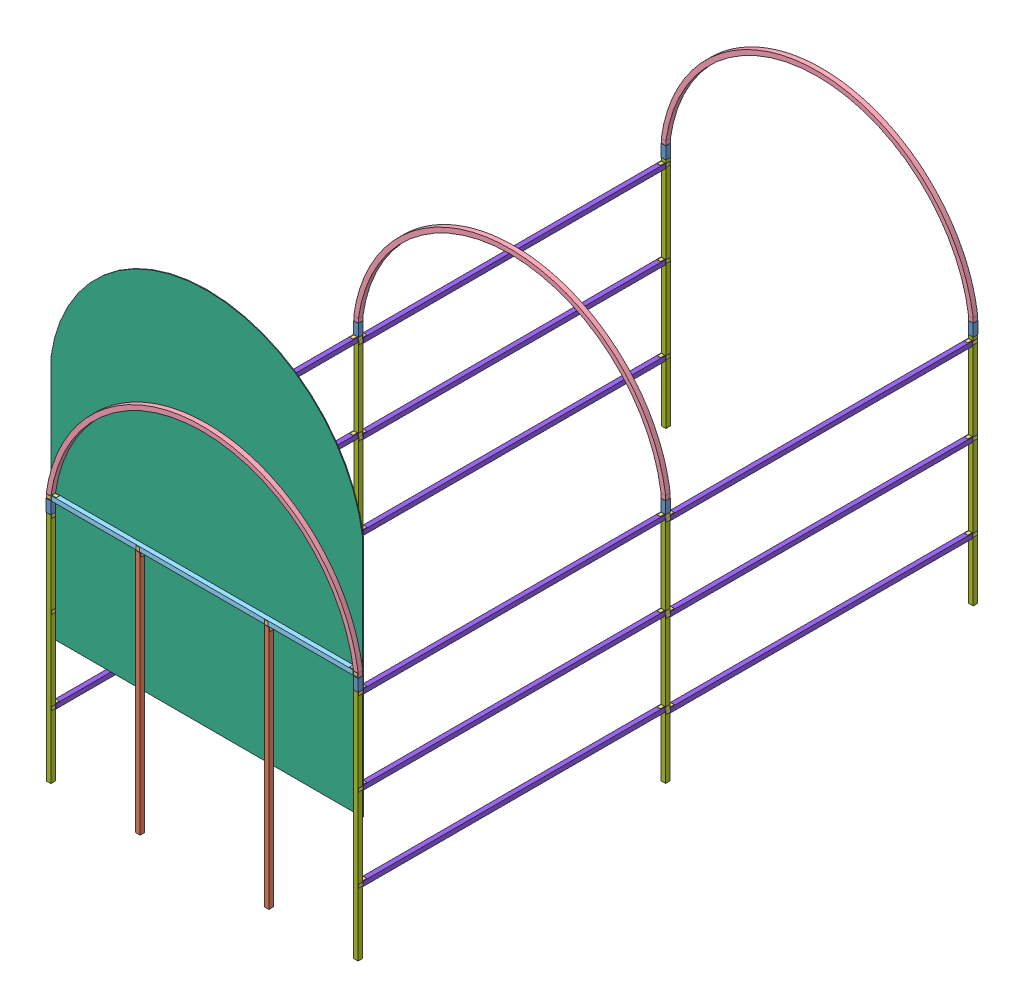
SolidWorks assembly SolarDrying, configuration Default. Lengths in mm.
Overall size (2062 2546.04 4095).
87 component instances, 8 part files, 50 mates.
Components (placement in the parent):
- Vertical joint-1: Vertical joint [Default] at (-1015 770.5 -2037.8) size (32 80 32)
- VerticalBar-1: VerticalBar [Default] at (-425 0 -2037.8) x (-1 0 0) z (0 0 1) size (30 1615 30)
- Wrapper-1: Wrapper [Default] at (-425 780.5 -2037.8) x (0 0 -1) z (0 1 0) size (22 32 30)
- Arc_Bar-1: Arc_Bar [Default] at (0 838.5301 -2037.8) x (0 0 -1) z (1 0 0) size (30.03 960.01 2060)
- LateralBar-1: LateralBar [Default] at (0 826.5 -2037.8) x (0 0 -1) z (1 0 0) size (30 30 1992)
- Back_Wall-1: Back_Wall [Default] at (0 800 -2055.3) size (2060 2500 5) (hidden)
- Wrapper-4: Wrapper [Default] at (-1027 826.5 -2037.8) x (0 1 0) z (1 0 0) size (22 32 30)
- Wrapper-5: Wrapper [Default] at (-969 826.5 -2037.8) x (0 0 1) z (-1 0 0) size (22 32 30)
- VerticalBar_Corners-1: VerticalBar_Corners [Default] at (-1015 -14.4849 -2037.8) size (30 1586.03 30)
- Wrapper-8: Wrapper [Default] at (-425 838.5 -2037.8) x (1 0 0) z (0 -1 0) size (22 32 30)
- VerticalBar-2: VerticalBar [Default] at (425 0 -2037.8) x (1 0 0) z (0 0 -1) size (30 1615 30)
- Wrapper-9: Wrapper [Default] at (425 838.5 -2037.8) x (1 0 0) z (0 -1 0) size (22 32 30)
- Wrapper-10: Wrapper [Default] at (425 780.5 -2037.8) x (0 0 1) z (0 1 0) size (22 32 30)
- VerticalBar_Corners-2: VerticalBar_Corners [Default] at (1015 -14.4849 -2037.8) x (-1 0 0) z (0 0 -1) size (30 1586.03 30)
- Vertical joint-2: Vertical joint [Default] at (1015 770.5 -2037.8) x (-1 0 0) z (0 0 -1) size (32 80 32)
- Wrapper-11: Wrapper [Default] at (1027 826.5 -2037.8) x (0 -1 0) z (-1 0 0) size (22 32 30)
- Wrapper-12: Wrapper [Default] at (969 826.5 -2037.8) x (0 0 -1) z (1 0 0) size (22 32 30)
- VerticalBar_Corners-7: VerticalBar_Corners [Default] at (-1015 -14.4849 -4069.3) size (30 1586.03 30)
- VerticalBar_Corners-8: VerticalBar_Corners [Default] at (-1015 -14.4849 -6100.8) size (30 1586.03 30)
- Vertical joint-7: Vertical joint [Default] at (-1015 770.5 -4069.3) size (32 80 32)
- Vertical joint-8: Vertical joint [Default] at (-1015 770.5 -6100.8) size (32 80 32)
- VerticalBar_Corners-9: VerticalBar_Corners [Default] at (1015 -14.4849 -4069.3) x (-1 0 0) z (0 0 -1) size (30 1586.03 30)
- VerticalBar_Corners-10: VerticalBar_Corners [Default] at (1015 -14.4849 -6100.8) x (-1 0 0) z (0 0 -1) size (30 1586.03 30)
- Vertical joint-9: Vertical joint [Default] at (1015 770.5 -4069.3) x (-1 0 0) z (0 0 -1) size (32 80 32)
- Vertical joint-10: Vertical joint [Default] at (1015 770.5 -6100.8) x (-1 0 0) z (0 0 -1) size (32 80 32)
- Arc_Bar-4: Arc_Bar [Default] at (0 838.5301 -4069.3) x (0 0 -1) z (1 0 0) size (30.03 960.01 2060)
- Arc_Bar-5: Arc_Bar [Default] at (0 838.5301 -6100.8) x (0 0 -1) z (1 0 0) size (30.03 960.01 2060)
- Wrapper-13: Wrapper [Default] at (1015 719.5 -2025.8) x (0 1 0) z (0 0 -1) size (22 32 30)
- Wrapper-15: Wrapper [Default] at (1015 717.5 -2083.8) size (22 32 30)
- Wrapper-16: Wrapper [Default] at (1015 719.5 -4081.3) x (0 -1 0) z (0 0 1) size (22 32 30)
- Wrapper-17: Wrapper [Default] at (1015 717.5 -4023.3) x (-1 0 0) z (0 0 -1) size (22 32 30)
- HorizontalBarSides-1: HorizontalBarSides [Default] at (1015 717.5 -4051.3) size (30 30 1995.5)
- Wrapper-22: Wrapper [Default] at (1015 697.5 -4057.3) x (0 1 0) z (0 0 -1) size (22 32 30)
- Wrapper-23: Wrapper [Default] at (1015 695.5 -4115.3) size (22 32 30)
- HorizontalBarSides-3: HorizontalBarSides [Default] at (1015 695.5 -6082.8) size (30 30 1995.5)
- Wrapper-24: Wrapper [Default] at (1015 697.5 -6112.8) x (0 -1 0) z (0 0 1) size (22 32 30)
- Wrapper-25: Wrapper [Default] at (1015 695.5 -6054.8) x (-1 0 0) z (0 0 -1) size (22 32 30)
- Wrapper-26: Wrapper [Default] at (1015 147.5 -6112.8) x (0 -1 0) z (0 0 1) size (22 32 30)
- Wrapper-27: Wrapper [Default] at (1015 -402.5 -6112.8) x (0 -1 0) z (0 0 1) size (22 32 30)
- Wrapper-28: Wrapper [Default] at (1015 145.5 -6054.8) x (-1 0 0) z (0 0 -1) size (22 32 30)
- Wrapper-29: Wrapper [Default] at (1015 -404.5 -6054.8) x (-1 0 0) z (0 0 -1) size (22 32 30)
- HorizontalBarSides-4: HorizontalBarSides [Default] at (1015 145.5 -6082.8) size (30 30 1995.5)
- HorizontalBarSides-5: HorizontalBarSides [Default] at (1015 -404.5 -6082.8) size (30 30 1995.5)
- Wrapper-30: Wrapper [Default] at (1015 145.5 -4115.3) size (22 32 30)
- Wrapper-31: Wrapper [Default] at (1015 -404.5 -4115.3) size (22 32 30)
- Wrapper-32: Wrapper [Default] at (1015 147.5 -4057.3) x (0 1 0) z (0 0 -1) size (22 32 30)
- Wrapper-33: Wrapper [Default] at (1015 -402.5 -4057.3) x (0 1 0) z (0 0 -1) size (22 32 30)
- Wrapper-34: Wrapper [Default] at (1015 169.5 -4081.3) x (0 -1 0) z (0 0 1) size (22 32 30)
- Wrapper-35: Wrapper [Default] at (1015 -380.5 -4081.3) x (0 -1 0) z (0 0 1) size (22 32 30)
- Wrapper-36: Wrapper [Default] at (1015 167.5 -4023.3) x (-1 0 0) z (0 0 -1) size (22 32 30)
- Wrapper-37: Wrapper [Default] at (1015 -382.5 -4023.3) x (-1 0 0) z (0 0 -1) size (22 32 30)
- HorizontalBarSides-6: HorizontalBarSides [Default] at (1015 167.5 -4051.3) size (30 30 1995.5)
- HorizontalBarSides-7: HorizontalBarSides [Default] at (1015 -382.5 -4051.3) size (30 30 1995.5)
- Wrapper-38: Wrapper [Default] at (1015 169.5 -2025.8) x (0 1 0) z (0 0 -1) size (22 32 30)
- Wrapper-39: Wrapper [Default] at (1015 -380.5 -2025.8) x (0 1 0) z (0 0 -1) size (22 32 30)
- Wrapper-40: Wrapper [Default] at (1015 167.5 -2083.8) size (22 32 30)
- Wrapper-41: Wrapper [Default] at (1015 -382.5 -2083.8) size (22 32 30)
- Wrapper-42: Wrapper [Default] at (-1015 697.5 -6112.8) x (0 1 0) z (0 0 1) size (22 32 30)
- Wrapper-43: Wrapper [Default] at (-1015 695.5 -6054.8) x (-1 0 0) z (0 0 -1) size (22 32 30)
- HorizontalBarSides-8: HorizontalBarSides [Default] at (-1015 695.5 -4087.3) x (-1 0 0) z (0 0 -1) size (30 30 1995.5)
- Wrapper-44: Wrapper [Default] at (-1015 695.5 -4115.3) size (22 32 30)
- Wrapper-45: Wrapper [Default] at (-1015 697.5 -4057.3) x (0 -1 0) z (0 0 -1) size (22 32 30)
- Wrapper-46: Wrapper [Default] at (-1015 719.5 -4081.3) x (0 1 0) z (0 0 1) size (22 32 30)
- Wrapper-47: Wrapper [Default] at (-1015 717.5 -4023.3) x (-1 0 0) z (0 0 -1) size (22 32 30)
- HorizontalBarSides-9: HorizontalBarSides [Default] at (-1015 717.5 -2055.8) x (-1 0 0) z (0 0 -1) size (30 30 1995.5)
- Wrapper-48: Wrapper [Default] at (-1015 719.5 -2025.8) x (0 -1 0) z (0 0 -1) size (22 32 30)
- Wrapper-49: Wrapper [Default] at (-1015 717.5 -2083.8) size (22 32 30)
- Wrapper-50: Wrapper [Default] at (-1015 147.5 -6112.8) x (0 1 0) z (0 0 1) size (22 32 30)
- Wrapper-51: Wrapper [Default] at (-1015 -402.5 -6112.8) x (0 1 0) z (0 0 1) size (22 32 30)
- Wrapper-52: Wrapper [Default] at (-1015 145.5 -6054.8) x (-1 0 0) z (0 0 -1) size (22 32 30)
- Wrapper-53: Wrapper [Default] at (-1015 -404.5 -6054.8) x (-1 0 0) z (0 0 -1) size (22 32 30)
- HorizontalBarSides-10: HorizontalBarSides [Default] at (-1015 145.5 -4087.3) x (-1 0 0) z (0 0 -1) size (30 30 1995.5)
- HorizontalBarSides-11: HorizontalBarSides [Default] at (-1015 -404.5 -4087.3) x (-1 0 0) z (0 0 -1) size (30 30 1995.5)
- Wrapper-54: Wrapper [Default] at (-1015 145.5 -4115.3) size (22 32 30)
- Wrapper-55: Wrapper [Default] at (-1015 -404.5 -4115.3) size (22 32 30)
- Wrapper-56: Wrapper [Default] at (-1015 147.5 -4057.3) x (0 -1 0) z (0 0 -1) size (22 32 30)
- Wrapper-57: Wrapper [Default] at (-1015 -402.5 -4057.3) x (0 -1 0) z (0 0 -1) size (22 32 30)
- Wrapper-58: Wrapper [Default] at (-1015 169.5 -4081.3) x (0 1 0) z (0 0 1) size (22 32 30)
- Wrapper-59: Wrapper [Default] at (-1015 -380.5 -4081.3) x (0 1 0) z (0 0 1) size (22 32 30)
- Wrapper-60: Wrapper [Default] at (-1015 167.5 -4023.3) x (-1 0 0) z (0 0 -1) size (22 32 30)
- Wrapper-61: Wrapper [Default] at (-1015 -382.5 -4023.3) x (-1 0 0) z (0 0 -1) size (22 32 30)
- HorizontalBarSides-12: HorizontalBarSides [Default] at (-1015 167.5 -2055.8) x (-1 0 0) z (0 0 -1) size (30 30 1995.5)
- HorizontalBarSides-13: HorizontalBarSides [Default] at (-1015 -382.5 -2055.8) x (-1 0 0) z (0 0 -1) size (30 30 1995.5)
- Wrapper-62: Wrapper [Default] at (-1015 169.5 -2025.8) x (0 -1 0) z (0 0 -1) size (22 32 30)
- Wrapper-63: Wrapper [Default] at (-1015 -380.5 -2025.8) x (0 -1 0) z (0 0 -1) size (22 32 30)
- Wrapper-64: Wrapper [Default] at (-1015 167.5 -2083.8) size (22 32 30)
- Wrapper-65: Wrapper [Default] at (-1015 -382.5 -2083.8) size (22 32 30)
Mates (geometry in assembly coordinates):
- Coincident1: coincident anti-aligned: plane of Back_Wall-1 through (1030 0 -2052.8) normal (0 -1 0)
- Distance1: distance = 2052.8 mm aligned: plane of Back_Wall-1 through (0 1460.6111 -2052.8) normal (0 0 1)
- Coincident6: coincident anti-aligned: plane of LateralBar-1 through (996 811.5 -2052.8) normal (0 0 -1); plane of Back_Wall-1 through (0 1460.6111 -2052.8) normal (0 0 1)
- Coincident12: coincident aligned: plane of Back_Wall-1 through (0 800 -2055.3) normal (1 0 0)
- Coincident15: coincident anti-aligned: plane of LateralBar-1 through (996 841.5 -2022.8) normal (0 1 0); plane of Wrapper-5 through (-996 841.5 -2048.8) normal (0 -1 0)
- Coincident16: coincident anti-aligned: plane of LateralBar-1 through (996 811.5 -2022.8) normal (0 -1 0); plane of Wrapper-5 through (-969 811.5 -2048.8) normal (0 1 0)
- Parallel4: parallel aligned: plane of LateralBar-1 through (996 811.5 -2052.8) normal (0 0 -1); plane of Wrapper-5 through (-996 842.5 -2048.8) normal (0 0 -1)
- Coincident19: coincident anti-aligned: plane of LateralBar-1 through (0 826.5 -2037.8) normal (0 0 -1); plane of Wrapper-5 through (-969 826.5 -2037.8) normal (0 0 1)
- Coincident23: coincident anti-aligned: plane of Wrapper-4 through (-998 815.5 -2050.8) normal (-1 0 0); plane of Wrapper-5 through (-998 813.5 -2048.8) normal (1 0 0)
- Coincident25: coincident aligned: plane of Wrapper-4 through (-1027 826.5 -2037.8) normal (0 1 0); plane of Wrapper-5 through (-969 826.5 -2037.8) normal (0 1 0)
- Coincident26: coincident aligned: plane of Arc_Bar-1; plane of LateralBar-1 through (0 826.5 -2037.8) normal (1 0 0)
- Coincident27: coincident aligned: plane of Arc_Bar-1; plane of LateralBar-1 through (0 826.5 -2037.8) normal (1 0 0)
- Parallel5: parallel anti-aligned: line of Arc_Bar-1 through (-1000 837.5 -2022.8) axis (0 0 -1); line of LateralBar-1 through (-996 841.5 -2052.8) axis (0 0 1)
- Coincident31: coincident: point of Arc_Bar-1; point of Wrapper-4
- Coincident32: coincident anti-aligned: plane of Vertical joint-1 through (-1000 810.5 -2052.8) normal (0 0 1); plane of Arc_Bar-1 through (0 778.5301 -2052.8) normal (0 0 -1)
- Coincident33: coincident anti-aligned: plane of Vertical joint-1 through (-1030 810.5 -2052.8) normal (1 0 0); plane of Arc_Bar-1 through (-1030 778.5301 -2037.8) normal (-1 0 0)
- Coincident34: coincident anti-aligned: plane of Wrapper-4 through (-998 815.5 -2050.8) normal (-1 0 0); plane of Wrapper-5 through (-998 813.5 -2048.8) normal (1 0 0)
- Coincident35: coincident aligned: plane of Wrapper-4 through (-1027 826.5 -2037.8) normal (0 0 1); plane of Wrapper-5 through (-969 826.5 -2037.8) normal (0 0 1)
- Coincident36: coincident anti-aligned: plane of Vertical joint-1 through (-1015 810.5 -2037.8) normal (0 1 0); plane of Wrapper-5 through (-969 810.5 -2048.8) normal (0 -1 0)
- Coincident42: coincident anti-aligned: line of VerticalBar-1 through (-410 807.5 -2052.8) axis (0 0 1); line of Wrapper-1 through (-410 807.5 -2026.8) axis (0 0 -1)
- Coincident43: coincident aligned: line of VerticalBar-1 through (-440 807.5 -2022.8) axis (0 0 -1); line of Wrapper-1 through (-440 807.5 -2026.8) axis (0 0 -1)
- Coincident44: coincident anti-aligned: plane of VerticalBar-1 through (-425 0 -2037.8) normal (0 0 1); plane of Wrapper-1 through (-425 780.5 -2037.8) normal (0 0 -1)
- Coincident45: coincident anti-aligned: plane of VerticalBar-1 through (-425 0 -2037.8) normal (0 0 1); plane of LateralBar-1 through (0 826.5 -2037.8) normal (0 0 -1)
- Parallel6: parallel anti-aligned: plane of VerticalBar-1 through (-425 0 -2037.8) normal (-1 0 0); plane of LateralBar-1 through (0 826.5 -2037.8) normal (1 0 0)
- Distance3: distance = 425 mm anti-aligned: plane of VerticalBar-1 through (-425 0 -2037.8) normal (-1 0 0); plane of LateralBar-1 through (0 826.5 -2037.8) normal (1 0 0)
- Coincident48: coincident anti-aligned: plane of Wrapper-1 through (-412 809.5 -2026.8) normal (0 -1 0); plane of Wrapper-8 through (-436 809.5 -2050.8) normal (0 1 0)
- Coincident49: coincident anti-aligned: plane of Wrapper-1 through (-425 780.5 -2037.8) normal (-1 0 0); plane of Wrapper-8 through (-425 838.5 -2037.8) normal (1 0 0)
- Coincident50: coincident anti-aligned: plane of Wrapper-1 through (-425 780.5 -2037.8) normal (0 0 -1); plane of Wrapper-8 through (-425 838.5 -2037.8) normal (0 0 1)
- Coincident51: coincident anti-aligned: line of LateralBar-1 through (996 811.5 -2022.8) axis (-1 0 0); line of Wrapper-8 through (-436 811.5 -2022.8) axis (1 0 0)
- Coincident52: coincident anti-aligned: plane of Arc_Bar-1 through (0 778.5301 -2037.8) normal (0 -1 0); plane of VerticalBar_Corners-1 through (-1015 778.5301 -2037.8) normal (0 1 0)
- Coincident53: coincident anti-aligned: plane of Vertical joint-1 through (-1000 810.5 -2052.8) normal (0 0 1); plane of VerticalBar_Corners-1 through (-1030 778.5301 -2052.8) normal (0 0 -1)
- Coincident54: coincident anti-aligned: plane of Vertical joint-1 through (-1000 810.5 -2052.8) normal (-1 0 0); plane of VerticalBar_Corners-1 through (-1000 778.5301 -2052.8) normal (1 0 0)
- Coincident57: coincident anti-aligned: plane of VerticalBar-1 through (-425 0 -2037.8) normal (0 -1 0)
- Coincident58: coincident anti-aligned: line of VerticalBar_Corners-2 through (1000 778.5301 -2052.8) axis (0 -1 0); line of Wrapper-13 through (1000 708.5 -2052.8) axis (0 1 0)
- Coincident59: coincident anti-aligned: line of VerticalBar_Corners-2 through (1030 778.5301 -2052.8) axis (0 -1 0); line of Wrapper-13 through (1030 708.5 -2052.8) axis (0 1 0)
- Coincident60: coincident aligned: plane of Wrapper-13 through (1015 719.5 -2025.8) normal (1 0 0); plane of Wrapper-15 through (1015 717.5 -2083.8) normal (1 0 0)
- Coincident61: coincident aligned: plane of Wrapper-13 through (1015 719.5 -2025.8) normal (1 0 0); plane of Wrapper-15 through (1015 717.5 -2083.8) normal (1 0 0)
- Coincident63: coincident anti-aligned: plane of Wrapper-13 through (1002 708.5 -2054.8) normal (0 0 1); plane of Wrapper-15 through (1004 704.5 -2054.8) normal (0 0 -1)
- Coincident64: coincident anti-aligned: plane of Vertical joint-2 through (1015 730.5 -2037.8) normal (0 -1 0); plane of Wrapper-13 through (1031 730.5 -2052.8) normal (0 1 0)
- Coincident65: coincident aligned: line of Wrapper-13 through (1002 730.5 -2054.8) axis (1 0 0); line of Wrapper-15 through (1004 730.5 -2054.8) axis (1 0 0)
- Coincident67: coincident aligned: line of VerticalBar_Corners-9 through (1000 778.5301 -4054.3) axis (0 -1 0); line of Wrapper-16 through (1000 730.5 -4054.3) axis (0 -1 0)
- Coincident68: coincident aligned: unknown of Arc_Bar-1
- Coincident69: coincident aligned: line of VerticalBar_Corners-9 through (1030 778.5301 -4054.3) axis (0 -1 0); line of Wrapper-16 through (1030 730.5 -4054.3) axis (0 -1 0)
- Coincident70: coincident anti-aligned: plane of Vertical joint-9 through (1015 730.5 -4069.3) normal (0 -1 0); plane of Wrapper-16 through (1031 730.5 -4054.3) normal (0 1 0)
- Coincident71: coincident anti-aligned: plane of Wrapper-16 through (1002 730.5 -4052.3) normal (0 0 -1); plane of Wrapper-17 through (1026 704.5 -4052.3) normal (0 0 1)
- Coincident72: coincident anti-aligned: line of Wrapper-16 through (1002 730.5 -4052.3) axis (1 0 0); line of Wrapper-17 through (1026 730.5 -4052.3) axis (-1 0 0)
- Coincident73: coincident anti-aligned: plane of Wrapper-16 through (1015 719.5 -4081.3) normal (1 0 0); plane of Wrapper-17 through (1015 717.5 -4023.3) normal (-1 0 0)
- Coincident74: coincident anti-aligned: plane of Wrapper-16 through (1002 730.5 -4051.3) normal (0 0 1); plane of HorizontalBarSides-1 through (1015 717.5 -4051.3) normal (0 0 -1)
- Coincident75: coincident anti-aligned: plane of Wrapper-17 through (1015 717.5 -4023.3) normal (-1 0 0); plane of HorizontalBarSides-1 through (1015 717.5 -4051.3) normal (1 0 0)
- Coincident76: coincident anti-aligned: plane of Wrapper-15 through (1004 732.5 -2056.8) normal (0 -1 0); plane of HorizontalBarSides-1 through (1030 732.5 -2055.8) normal (0 1 0)
